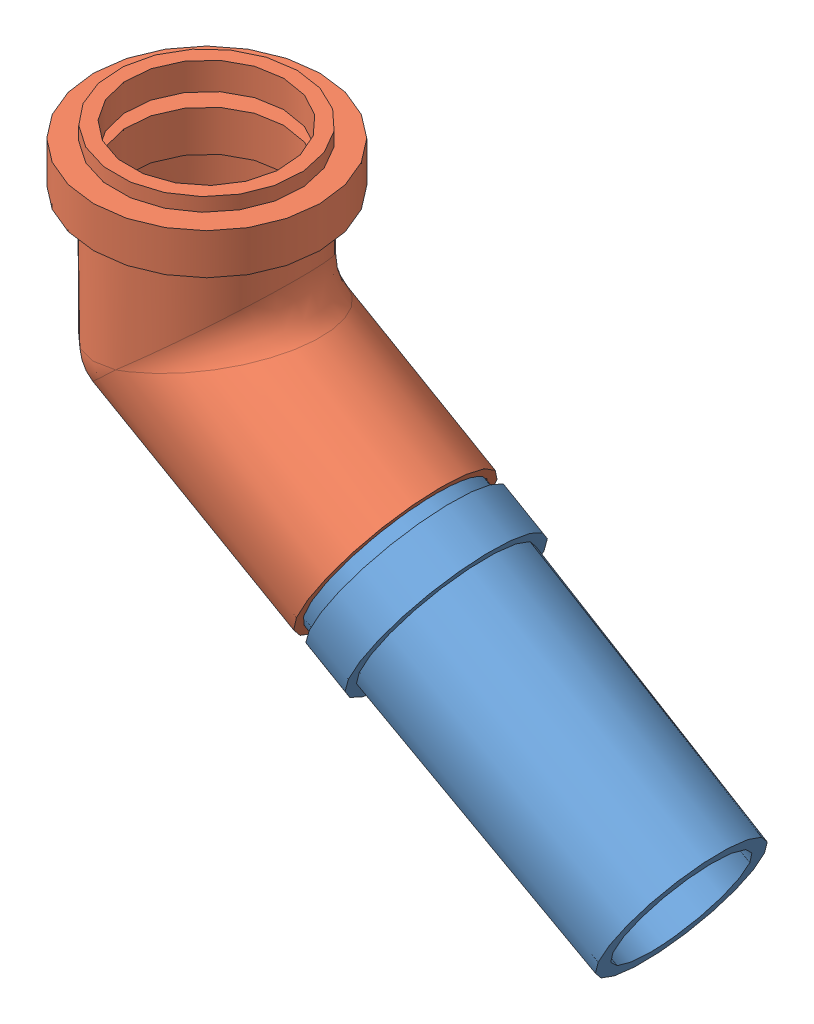
SolidWorks assembly СоединительПЛ, configuration По умолчанию. Lengths in mm.
Overall size (144.77 120.01 50).
2 component instances, 2 part files, 2 mates.
Components (placement in the parent):
- ТрубаПЛ40-1: ТрубаПЛ40 [По умолчанию] at (18.2632 -29.7707 0) x (-0.489832 -0.848413 -0.200647) z (-0.100324 -0.173766 0.979664) size (40 109.44 40)
- Сгон6040-1: Сгон6040 [По умолчанию] at origin size (76.77 78.75 50)
Mates (geometry in assembly coordinates):
- Совпадение1: coordinate: point of Сгон6040-1; point of assembly
- Концентричный1: concentric anti-aligned: cylinder of ТрубаПЛ40-1 through (104.8657 -79.7707 0) axis (-0.866025 0.5 0) radius 20; cylinder of Сгон6040-1 through (-22.2512 -6.3798 0) axis (0.866025 -0.5 0) radius 20.1496
